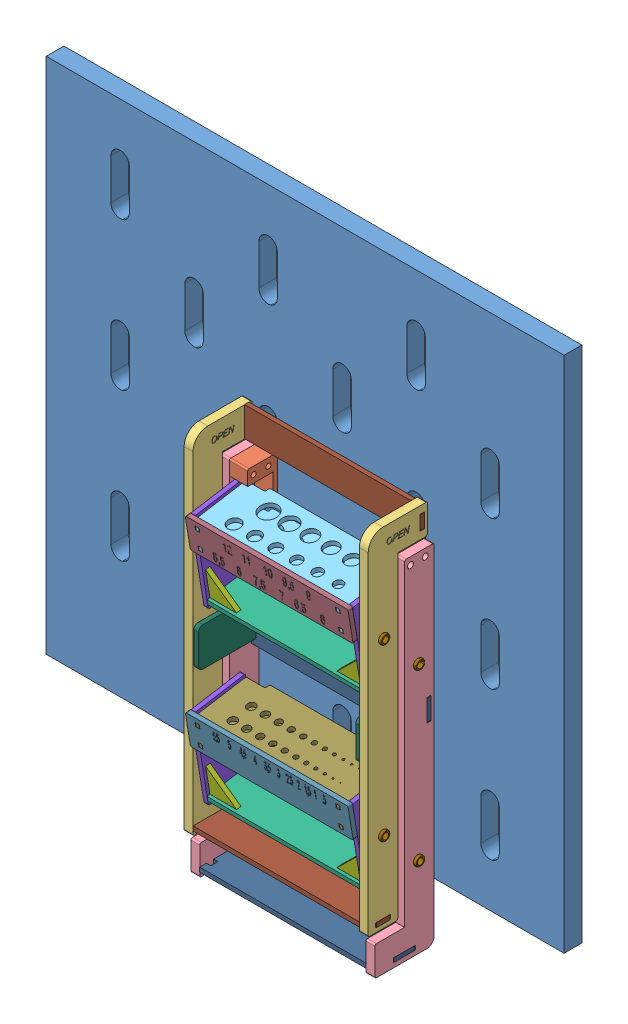
SolidWorks assembly 0 Органайзер свёрла, configuration По умолчанию. Lengths in mm.
Overall size (350 388.75 67.87).
37 component instances, 15 part files, 100 mates.
Components (placement in the parent):
- 1 Стенка-1: 1 Стенка [По умолчанию] at origin size (350 350 12)
- 2 Кронштейн свёрла-1: 2 Кронштейн свёрла [По умолчанию] at (43.8 136.25 12) size (12.4 30 35.1)
- 2 Кронштейн свёрла-2: 2 Кронштейн свёрла [По умолчанию] at (143.8 136.25 12) size (12.4 30 35.1)
- 4 Стенка подвижная свёрла-1: 4 Стенка подвижная свёрла [По умолчанию] at (37.8 -62.2036 36.5858) size (6 235 40)
- 4 Стенка подвижная свёрла-2: 4 Стенка подвижная свёрла [По умолчанию] at (156.2 -62.2036 36.5858) size (6 235 40)
- 3 Стенка основа свёрла-1: 3 Стенка основа свёрла [По умолчанию] at (37.8 146.25 12) size (6 235 40)
- 3 Стенка основа свёрла-2: 3 Стенка основа свёрла [По умолчанию] at (156.2 146.25 12) size (6 235 40)
- 7 Полка ячейки верхняя-2: 7 Полка ячейки верхняя [По умолчанию] at (100.2 129.8865 41.0226) x (-1 0 0) z (0 -0.986932 -0.161135) size (110 41 3)
- 6 Полка ячейки нижняя-2: 6 Полка ячейки нижняя [По умолчанию] at (100.2 72.7151 51.0412) x (1 0 0) z (0 -0.161135 0.986932) size (110 3 35)
- 10 Уголок свёрла-1: 10 Уголок свёрла [По умолчанию] at (45.2 86.3468 48.2259) x (1 0 0) z (0 -0.161135 0.986932) size (21 21 3)
- 10 Уголок свёрла-2: 10 Уголок свёрла [По умолчанию] at (142.2 73.5167 46.1312) x (0 0.986932 0.161135) z (0 -0.161135 0.986932) size (21 21 3)
- 5 Стенка ячейки-3: 5 Стенка ячейки [По умолчанию] at (152.2 102.3381 36.5754) x (0 0.161135 -0.986932) z (1 0 0) size (38 60 3)
- 5 Стенка ячейки-4: 5 Стенка ячейки [По умолчанию] at (45.2 102.3381 36.5754) x (0 0.161135 -0.986932) z (1 0 0) size (38 60 3)
- 9 штифт-1: 9 штифт [По умолчанию] at (44.3 107.7964 46.5858) x (-1 0 0) z (0 0.755067 -0.655647) size (14.3 7.8 7.8)
- 9 штифт-2: 9 штифт [По умолчанию] at (155.7 81.25 23) size (14.3 7.8 7.8)
- 9 штифт-4: 9 штифт [По умолчанию] at (44.3 81.25 23) x (-1 0 0) z (0 -0.824555 -0.565781) size (14.3 7.8 7.8)
- 9 штифт-5: 9 штифт [По умолчанию] at (155.7 107.7964 46.5858) x (1 0 0) z (0 -0.809118 0.587647) size (14.3 7.8 7.8)
- 6 Полка ячейки нижняя-5: 6 Полка ячейки нижняя [По умолчанию] at (100.275 -42.2849 51.0412) x (1 0 0) z (0 -0.161135 0.986932) size (110 3 35)
- 10 Уголок свёрла-7: 10 Уголок свёрла [По умолчанию] at (45.275 -28.6532 48.2259) x (1 0 0) z (0 -0.161135 0.986932) size (21 21 3)
- 5 Стенка ячейки-9: 5 Стенка ячейки [По умолчанию] at (152.2 -12.6619 36.5754) x (0 0.161135 -0.986932) z (1 0 0) size (38 60 3)
- 10 Уголок свёрла-8: 10 Уголок свёрла [По умолчанию] at (142.2 -41.4914 46.1805) x (0 0.986932 0.161135) z (0 -0.161135 0.986932) size (21 21 3)
- 5 Стенка ячейки-10: 5 Стенка ячейки [По умолчанию] at (45.275 -12.6619 36.5754) x (0 0.161135 -0.986932) z (1 0 0) size (38 60 3)
- 9 штифт-9: 9 штифт [По умолчанию] at (44.3 -7.2036 46.5858) x (-1 0 0) z (0 0.849471 -0.527636) size (14.3 7.8 7.8)
- 9 штифт-10: 9 штифт [По умолчанию] at (155.7 -33.75 23) x (1 0 0) z (0 0.562749 -0.826628) size (14.3 7.8 7.8)
- 9 штифт-11: 9 штифт [По умолчанию] at (44.3 -33.75 23) x (-1 0 0) z (0 -0.724419 -0.68936) size (14.3 7.8 7.8)
- 9 штифт-12: 9 штифт [По умолчанию] at (155.7 -7.2036 46.5858) x (1 0 0) z (0 -0.892056 0.451925) size (14.3 7.8 7.8)
- 11 низ-1: 11 низ [По умолчанию] at (99.95 -85.655 32.05) size (124.5 3 40)
- 12 верх-1: 12 верх [По умолчанию] at (99.95 162.8464 18.6808) x (1 0 0) z (0 -1 0) size (124.5 3 20)
- 7 Полка ячейки верхняя-6: 7 Полка ячейки верхняя [По умолчанию] at (100.2 117.0564 38.9278) x (-1 0 0) z (0 -0.986932 -0.161135) size (110 41 3)
- 7.1 Полка ячейки верхняя -1: 7.1 Полка ячейки верхняя  [По умолчанию] at (100.275 14.8865 41.0226) x (-1 0 0) z (0 -0.986932 -0.161135) size (110 41 3)
- 13.1 маркировка свёрла верх-1: 13.1 маркировка свёрла верх [По умолчанию] at (100.125 118.8555 58.4731) x (1 0 0) z (0 -0.161135 0.986932) size (110 22 3)
- 7.1 Полка ячейки верхняя -4: 7.1 Полка ячейки верхняя  [По умолчанию] at (100.275 2.0564 38.9278) x (-1 0 0) z (0 -0.986932 -0.161135) size (110 41 3)
- 13.2 маркировка свёрла низ-1: 13.2 маркировка свёрла низ [По умолчанию] at (100.2 3.8555 58.4731) x (1 0 0) z (0 -0.161135 0.986932) size (110 40.65 3)
- 12 верх-3: 12 верх [По умолчанию] at (100.05 -59.2986 46.5358) size (124.5 3 20)
- 11 низ-2: 11 низ [По умолчанию] at (99.95 50.7 13.915) x (1 0 0) z (0 -1 0) size (124.5 3 40)
- 14 направляюшая-1: 14 направляюшая [По умолчанию] at (156.2 50.625 36.415) x (0 0 1) z (-1 0 0) size (43.8 31 3)
- 14 направляюшая-2: 14 направляюшая [По умолчанию] at (46.8 50.625 36.415) x (0 0 1) z (-1 0 0) size (43.8 31 3)
Mates (geometry in assembly coordinates):
- Концентричный1: concentric anti-aligned: cylinder of 2 Кронштейн свёрла-2 through (156.2 141.25 28) axis (1 0 0) radius 1.7; cylinder of Стенка основа свёрла-2 through (162.2 141.25 28) axis (-1 0 0) radius 2
- Концентричный2: concentric anti-aligned: cylinder of 2 Кронштейн свёрла-2 through (156.2 141.25 18) axis (1 0 0) radius 1.7; cylinder of Стенка основа свёрла-2 through (162.2 141.25 18) axis (-1 0 0) radius 2
- Совпадение1: coincident anti-aligned: plane of 2 Кронштейн свёрла-2 through (156.2 136.25 12) normal (1 0 0); plane of Стенка основа свёрла-2 through (156.2 146.25 12) normal (-1 0 0)
- Концентричный3: concentric anti-aligned: cylinder of 2 Кронштейн свёрла-1 through (56.2 141.25 18) axis (1 0 0) radius 1.7; cylinder of 3 Стенка основа свёрла-1 through (43.8 141.25 18) axis (-1 0 0) radius 2
- Концентричный4: concentric anti-aligned: cylinder of 2 Кронштейн свёрла-1 through (56.2 141.25 28) axis (1 0 0) radius 1.7; cylinder of 3 Стенка основа свёрла-1 through (43.8 141.25 28) axis (-1 0 0) radius 2
- Совпадение2: coincident anti-aligned: plane of 2 Кронштейн свёрла-1 through (43.8 136.25 12) normal (-1 0 0); plane of 3 Стенка основа свёрла-1 through (43.8 146.25 12) normal (1 0 0)
- Концентричный7: concentric anti-aligned: cylinder of 1 Стенка-1 through (150 136.25 12) axis (0 0 -1) radius 6.25; cylinder of 2 Кронштейн свёрла-2 through (150 136.25 -23.513) axis (0 0 1) radius 6.2
- Концентричный9: concentric anti-aligned: cylinder of 1 Стенка-1 through (50 136.25 12) axis (0 0 -1) radius 6.25; cylinder of 2 Кронштейн свёрла-1 through (50 136.25 -23.513) axis (0 0 1) radius 6.2
- Совпадение15: coincident anti-aligned: plane of 1 Стенка-1 through (0 0 12) normal (0 0 1); plane of 2 Кронштейн свёрла-2 through (156.2 136.25 12) normal (0 0 -1)
- Параллельность1: parallel aligned: plane of 4 Стенка подвижная свёрла-1 through (43.8 172.7964 36.5858) normal (0 1 0); plane of 4 Стенка подвижная свёрла-2 through (162.2 172.7964 36.5858) normal (0 1 0)
- Совпадение18: coincident aligned: plane of 4 Стенка подвижная свёрла-1 through (43.8 -62.2036 36.5858) normal (1 0 0); plane of 3 Стенка основа свёрла-1 through (43.8 146.25 12) normal (1 0 0)
- Параллельность2: parallel aligned: plane of 4 Стенка подвижная свёрла-1 through (43.8 172.7964 36.5858) normal (0 1 0); plane of 4 Стенка подвижная свёрла-2 through (162.2 172.7964 36.5858) normal (0 1 0)
- Параллельность3: parallel aligned: plane of 1 Стенка-1 through (0 300 12) normal (0 1 0); plane of 4 Стенка подвижная свёрла-1 through (43.8 172.7964 36.5858) normal (0 1 0)
- Совпадение31: coincident anti-aligned: plane of 6 Полка ячейки нижняя-2 through (100.2 72.7151 51.0412) normal (0 -0.986932 -0.161135); plane of 5 Стенка ячейки-4 through (48.2 75.7847 32.2401) normal (0 0.986932 0.161135)
- Совпадение32: coincident anti-aligned: plane of 6 Полка ячейки нижняя-2 through (100.2 79.2208 29.812) normal (0 0.161135 -0.986932); plane of 5 Стенка ячейки-4 through (48.2 102.8134 33.664) normal (0 -0.161135 0.986932)
- Совпадение33: coincident aligned: plane of 6 Полка ячейки нижняя-2 through (45.2 75.6759 51.5246) normal (-1 0 0); plane of 5 Стенка ячейки-4 through (45.2 102.3381 36.5754) normal (-1 0 0)
- Совпадение34: coincident anti-aligned: plane of 6 Полка ячейки нижняя-2 through (100.2 75.6759 51.5246) normal (0 0.986932 0.161135); plane of 10 Уголок свёрла-1 through (45.2 75.9941 49.5754) normal (0 -0.986932 -0.161135)
- Совпадение35: coincident anti-aligned: plane of 10 Уголок свёрла-1 through (48.2 85.8634 51.1867) normal (-1 0 0); plane of 5 Стенка ячейки-4 through (48.2 102.3381 36.5754) normal (1 0 0)
- Совпадение36: coincident anti-aligned: plane of 10 Уголок свёрла-1 through (45.2 86.3468 48.2259) normal (0 0.161135 -0.986932); plane of 5 Стенка ячейки-4 through (48.2 100.0701 50.4665) normal (0 -0.161135 0.986932)
- Совпадение38: coincident anti-aligned: plane of 10 Уголок свёрла-2 through (152.2 73.0333 49.092) normal (1 0 0); plane of 5 Стенка ячейки-3 through (152.2 102.3381 36.5754) normal (-1 0 0)
- Совпадение39: coincident anti-aligned: plane of 6 Полка ячейки нижняя-2 through (100.2 75.6759 51.5246) normal (0 0.986932 0.161135); plane of 10 Уголок свёрла-2 through (142.2 75.9941 49.5754) normal (0 -0.986932 -0.161135)
- Совпадение40: coincident anti-aligned: plane of 10 Уголок свёрла-2 through (142.2 73.5167 46.1312) normal (0 0.161135 -0.986932); plane of 5 Стенка ячейки-3 through (155.2 100.0701 50.4665) normal (0 -0.161135 0.986932)
- Концентричный12: concentric aligned: cylinder of 3 Стенка основа свёрла-1 through (43.8 81.25 23) axis (-1 0 0) radius 3; cylinder of 5 Стенка ячейки-4 through (48.2 81.25 23) axis (-1 0 0) radius 3
- Концентричный13: concentric aligned: cylinder of 4 Стенка подвижная свёрла-1 through (43.8 107.7964 46.5858) axis (-1 0 0) radius 3; cylinder of 5 Стенка ячейки-4 through (48.2 107.7964 46.5858) axis (-1 0 0) radius 3
- Концентричный14: concentric aligned: cylinder of 4 Стенка подвижная свёрла-2 through (162.2 107.7964 46.5858) axis (-1 0 0) radius 3; cylinder of 5 Стенка ячейки-3 through (155.2 107.7964 46.5858) axis (-1 0 0) radius 3
- Совпадение42: coincident aligned: plane of 4 Стенка подвижная свёрла-2 through (156.2 -62.2036 36.5858) normal (-1 0 0); plane of Стенка основа свёрла-2 through (156.2 146.25 12) normal (-1 0 0)
- Совпадение43: coincident anti-aligned: plane of 1 Стенка-1 through (0 0 12) normal (0 0 1); plane of 3 Стенка основа свёрла-1 through (43.8 146.25 12) normal (0 0 -1)
- Концентричный20: concentric aligned: cylinder of 5 Стенка ячейки-3 through (155.2 81.25 23) axis (-1 0 0) radius 3; cylinder of 9 штифт-2 through (153.8908 81.25 23) axis (-1 0 0) radius 2.9
- Совпадение81: coincident anti-aligned: plane of Стенка основа свёрла-2 through (156.2 146.25 12) normal (-1 0 0); plane of 9 штифт-2 through (156.2 78.35 23) normal (1 0 0)
- Концентричный21: concentric anti-aligned: cylinder of 3 Стенка основа свёрла-1 through (43.8 81.25 23) axis (-1 0 0) radius 3; cylinder of 9 штифт-4 through (46.1092 81.25 23) axis (1 0 0) radius 2.9
- Совпадение82: coincident anti-aligned: plane of 3 Стенка основа свёрла-1 through (43.8 146.25 12) normal (1 0 0); plane of 9 штифт-4 through (43.8 79.6092 25.3912) normal (-1 0 0)
- Совпадение83: coincident anti-aligned: plane of 5 Стенка ячейки-3 through (155.2 102.3381 36.5754) normal (1 0 0); plane of 9 штифт-2 through (155.2 78.35 23) normal (-1 0 0)
- Концентричный22: concentric aligned: cylinder of 4 Стенка подвижная свёрла-2 through (162.2 107.7964 46.5858) axis (-1 0 0) radius 3; cylinder of 9 штифт-5 through (153.8908 107.7964 46.5858) axis (-1 0 0) radius 2.9
- Совпадение84: coincident anti-aligned: plane of 4 Стенка подвижная свёрла-2 through (156.2 -62.2036 36.5858) normal (-1 0 0); plane of 9 штифт-5 through (156.2 106.0922 44.2393) normal (1 0 0)
- Концентричный23: concentric anti-aligned: cylinder of 4 Стенка подвижная свёрла-1 through (43.8 107.7964 46.5858) axis (-1 0 0) radius 3; cylinder of 9 штифт-1 through (46.1092 107.7964 46.5858) axis (1 0 0) radius 2.9
- Совпадение85: coincident anti-aligned: plane of 4 Стенка подвижная свёрла-1 through (43.8 -62.2036 36.5858) normal (1 0 0); plane of 9 штифт-1 through (43.8 105.895 44.3961) normal (-1 0 0)
- Совпадение95: coincident anti-aligned: plane of 6 Полка ячейки нижняя-5 through (100.275 -42.2849 51.0412) normal (0 -0.986932 -0.161135); plane of 5 Стенка ячейки-10 through (48.275 -39.2153 32.2401) normal (0 0.986932 0.161135)
- Совпадение96: coincident anti-aligned: plane of 6 Полка ячейки нижняя-5 through (100.275 -35.7792 29.812) normal (0 0.161135 -0.986932); plane of 5 Стенка ячейки-10 through (48.275 -12.1866 33.664) normal (0 -0.161135 0.986932)
- Совпадение97: coincident aligned: plane of 6 Полка ячейки нижняя-5 through (45.275 -39.3241 51.5246) normal (-1 0 0); plane of 5 Стенка ячейки-10 through (45.275 -12.6619 36.5754) normal (-1 0 0)
- Совпадение98: coincident anti-aligned: plane of 6 Полка ячейки нижняя-5 through (100.275 -39.3241 51.5246) normal (0 0.986932 0.161135); plane of 10 Уголок свёрла-7 through (45.275 -39.0059 49.5754) normal (0 -0.986932 -0.161135)
- Совпадение99: coincident anti-aligned: plane of 10 Уголок свёрла-7 through (48.275 -29.1366 51.1867) normal (-1 0 0); plane of 5 Стенка ячейки-10 through (48.275 -12.6619 36.5754) normal (1 0 0)
- Совпадение100: coincident anti-aligned: plane of 10 Уголок свёрла-7 through (45.275 -28.6532 48.2259) normal (0 0.161135 -0.986932); plane of 5 Стенка ячейки-10 through (48.275 -14.9299 50.4665) normal (0 -0.161135 0.986932)
- Совпадение101: coincident anti-aligned: plane of 5 Стенка ячейки-9 through (152.2 -12.6619 36.5754) normal (-1 0 0); plane of 10 Уголок свёрла-8 through (152.2 -41.9748 49.1413) normal (1 0 0)
- Совпадение102: coincident anti-aligned: plane of 6 Полка ячейки нижняя-5 through (100.275 -39.3241 51.5246) normal (0 0.986932 0.161135); plane of 10 Уголок свёрла-8 through (142.2 -39.014 49.6247) normal (0 -0.986932 -0.161135)
- Концентричный25: concentric aligned: cylinder of 3 Стенка основа свёрла-1 through (43.8 -33.75 23) axis (-1 0 0) radius 3; cylinder of 5 Стенка ячейки-10 through (48.275 -33.75 23) axis (-1 0 0) radius 3
- Концентричный26: concentric aligned: cylinder of 4 Стенка подвижная свёрла-1 through (43.8 -7.2036 46.5858) axis (-1 0 0) radius 3; cylinder of 5 Стенка ячейки-10 through (48.275 -7.2036 46.5858) axis (-1 0 0) radius 3
- Совпадение105: coincident anti-aligned: plane of Стенка основа свёрла-2 through (156.2 146.25 12) normal (-1 0 0); plane of 9 штифт-10 through (156.2 -31.3528 24.632) normal (1 0 0)
- Концентричный28: concentric anti-aligned: cylinder of 3 Стенка основа свёрла-1 through (43.8 -33.75 23) axis (-1 0 0) radius 3; cylinder of 9 штифт-11 through (46.1092 -33.75 23) axis (1 0 0) radius 2.9
- Совпадение106: coincident anti-aligned: plane of 3 Стенка основа свёрла-1 through (43.8 146.25 12) normal (1 0 0); plane of 9 штифт-11 through (43.8 -35.7491 25.1008) normal (-1 0 0)
- Концентричный29: concentric aligned: cylinder of 4 Стенка подвижная свёрла-2 through (162.2 -7.2036 46.5858) axis (-1 0 0) radius 3; cylinder of 9 штифт-12 through (153.8908 -7.2036 46.5858) axis (-1 0 0) radius 2.9
- Совпадение107: coincident anti-aligned: plane of 4 Стенка подвижная свёрла-2 through (156.2 -62.2036 36.5858) normal (-1 0 0); plane of 9 штифт-12 through (156.2 -8.5142 43.9988) normal (1 0 0)
- Концентричный30: concentric anti-aligned: cylinder of 4 Стенка подвижная свёрла-1 through (43.8 -7.2036 46.5858) axis (-1 0 0) radius 3; cylinder of 9 штифт-9 through (46.1092 -7.2036 46.5858) axis (1 0 0) radius 2.9
- Совпадение108: coincident anti-aligned: plane of 4 Стенка подвижная свёрла-1 through (43.8 -62.2036 36.5858) normal (1 0 0); plane of 9 штифт-9 through (43.8 -8.7337 44.1223) normal (-1 0 0)
- Совпадение128: coincident aligned: plane of Стенка основа свёрла-2 through (162.2 146.25 12) normal (1 0 0); plane of 11 низ-1 through (162.2 -82.655 32.05) normal (1 0 0)
- Совпадение129: coincident anti-aligned: plane of Стенка основа свёрла-2 through (162.2 146.25 24.55) normal (0 0 1); plane of 11 низ-1 through (99.95 -82.655 24.55) normal (0 0 -1)
- Совпадение130: coincident anti-aligned: plane of Стенка основа свёрла-2 through (162.2 -85.655 12) normal (0 1 0); plane of 11 низ-1 through (99.95 -85.655 32.05) normal (0 -1 0)
- Совпадение131: coincident anti-aligned: plane of 4 Стенка подвижная свёрла-2 through (162.2 -62.2036 18.6808) normal (0 0 1); plane of 12 верх-1 through (99.95 162.8464 18.6808) normal (0 0 -1)
- Совпадение132: coincident anti-aligned: plane of 4 Стенка подвижная свёрла-2 through (162.2 157.8464 36.5858) normal (0 1 0); plane of 12 верх-1 through (99.95 157.8464 21.6808) normal (0 -1 0)
- Совпадение133: coincident aligned: plane of 4 Стенка подвижная свёрла-2 through (162.2 -62.2036 36.5858) normal (1 0 0); plane of 12 верх-1 through (162.2 162.8464 21.6808) normal (1 0 0)
- Совпадение134: coincident anti-aligned: plane of 5 Стенка ячейки-4 through (48.2 117.0483 38.9771) normal (0 -0.986932 -0.161135); plane of 7 Полка ячейки верхняя-6 through (100.2 117.0564 38.9278) normal (0 0.986932 0.161135)
- Совпадение135: coincident anti-aligned: plane of 5 Стенка ячейки-4 through (48.2 101.5405 41.4607) normal (0 0.161135 -0.986932); plane of 7 Полка ячейки верхняя-6 through (100.2 113.2899 43.3791) normal (0 -0.161135 0.986932)
- Совпадение136: coincident aligned: plane of 5 Стенка ячейки-4 through (45.2 102.3381 36.5754) normal (-1 0 0); plane of 7 Полка ячейки верхняя-6 through (45.2 114.0956 38.4444) normal (-1 0 0)
- Совпадение137: coincident anti-aligned: plane of 7 Полка ячейки верхняя-2 through (100.2 129.8865 41.0226) normal (0 0.986932 0.161135); plane of 5 Стенка ячейки-4 through (48.2 129.8784 41.0719) normal (0 -0.986932 -0.161135)
- Совпадение138: coincident anti-aligned: plane of 7 Полка ячейки верхняя-2 through (100.2 126.12 45.4738) normal (0 -0.161135 0.986932); plane of 5 Стенка ячейки-4 through (48.2 101.5405 41.4607) normal (0 0.161135 -0.986932)
- Совпадение139: coincident anti-aligned: plane of 7 Полка ячейки верхняя-2 through (48.2 126.9257 40.5392) normal (-1 0 0); plane of 5 Стенка ячейки-4 through (48.2 102.3381 36.5754) normal (1 0 0)
- Совпадение140: coincident anti-aligned: plane of 7 Полка ячейки верхняя-2 through (100.2 126.12 45.4738) normal (0 -0.161135 0.986932); plane of 5 Стенка ячейки-3 through (155.2 101.5405 41.4607) normal (0 0.161135 -0.986932)
- Совпадение141: coincident anti-aligned: plane of 7 Полка ячейки верхняя-2 through (100.2 129.8865 41.0226) normal (0 0.986932 0.161135); plane of 5 Стенка ячейки-3 through (155.2 129.8784 41.0719) normal (0 -0.986932 -0.161135)
- Совпадение142: coincident anti-aligned: plane of 7 Полка ячейки верхняя-2 through (152.2 126.9257 40.5392) normal (1 0 0); plane of 5 Стенка ячейки-3 through (152.2 102.3381 36.5754) normal (-1 0 0)
- Совпадение154: coincident anti-aligned: plane of 5 Стенка ячейки-10 through (48.275 14.8784 41.0719) normal (0 -0.986932 -0.161135); plane of 7.1 Полка ячейки верхняя -1 through (100.275 14.8865 41.0226) normal (0 0.986932 0.161135)
- Совпадение155: coincident anti-aligned: plane of 5 Стенка ячейки-10 through (48.275 -12.6619 36.5754) normal (1 0 0); plane of 7.1 Полка ячейки верхняя -1 through (48.275 11.9257 40.5392) normal (-1 0 0)
- Совпадение156: coincident anti-aligned: plane of 5 Стенка ячейки-10 through (48.275 -13.4595 41.4607) normal (0 0.161135 -0.986932); plane of 7.1 Полка ячейки верхняя -1 through (100.275 11.12 45.4738) normal (0 -0.161135 0.986932)
- Совпадение160: coincident anti-aligned: plane of 7 Полка ячейки верхняя-2 through (100.2 123.8641 59.2909) normal (0 -0.161135 0.986932); plane of 13.1 маркировка свёрла верх-1 through (100.125 118.8555 58.4731) normal (0 0.161135 -0.986932)
- Совпадение169: coincident anti-aligned: plane of 6 Полка ячейки нижняя-5 through (142.2 -39.3241 51.5246) normal (-1 0 0); plane of 10 Уголок свёрла-8 through (142.2 -41.9748 49.1413) normal (1 0 0)
- Совпадение170: coincident anti-aligned: plane of 6 Полка ячейки нижняя-5 through (100.275 -38.5306 46.6639) normal (0 -0.161135 0.986932); plane of 10 Уголок свёрла-8 through (142.2 -41.4914 46.1805) normal (0 0.161135 -0.986932)
- Совпадение171: coincident anti-aligned: plane of 5 Стенка ячейки-9 through (155.2 14.8784 41.0719) normal (0 -0.986932 -0.161135); plane of 7.1 Полка ячейки верхняя -1 through (100.275 14.8865 41.0226) normal (0 0.986932 0.161135)
- Совпадение172: coincident anti-aligned: plane of 5 Стенка ячейки-9 through (155.2 -13.4595 41.4607) normal (0 0.161135 -0.986932); plane of 7.1 Полка ячейки верхняя -1 through (100.275 11.12 45.4738) normal (0 -0.161135 0.986932)
- Совпадение173: coincident anti-aligned: plane of 5 Стенка ячейки-9 through (155.2 -12.6619 36.5754) normal (1 0 0); plane of 9 штифт-12 through (155.2 -8.5142 43.9988) normal (-1 0 0)
- Концентричный31: concentric aligned: cylinder of Стенка основа свёрла-2 through (162.2 -33.75 23) axis (-1 0 0) radius 3; cylinder of 9 штифт-10 through (153.8908 -33.75 23) axis (-1 0 0) radius 2.9
- Совпадение174: coincident anti-aligned: plane of 5 Стенка ячейки-10 through (48.275 2.0483 38.9771) normal (0 -0.986932 -0.161135); plane of 7.1 Полка ячейки верхняя -4 through (100.275 2.0564 38.9278) normal (0 0.986932 0.161135)
- Совпадение175: coincident anti-aligned: plane of 5 Стенка ячейки-10 through (48.275 -12.6619 36.5754) normal (1 0 0); plane of 7.1 Полка ячейки верхняя -4 through (48.275 -0.9044 38.4444) normal (-1 0 0)
- Совпадение176: coincident anti-aligned: plane of 5 Стенка ячейки-10 through (48.275 -13.4595 41.4607) normal (0 0.161135 -0.986932); plane of 7.1 Полка ячейки верхняя -4 through (100.275 -1.7101 43.3791) normal (0 -0.161135 0.986932)
- Совпадение177: coincident anti-aligned: plane of 5 Стенка ячейки-9 through (155.2 2.0483 38.9771) normal (0 -0.986932 -0.161135); plane of 7.1 Полка ячейки верхняя -4 through (100.275 2.0564 38.9278) normal (0 0.986932 0.161135)
- Совпадение178: coincident anti-aligned: plane of 5 Стенка ячейки-9 through (155.2 -13.4595 41.4607) normal (0 0.161135 -0.986932); plane of 7.1 Полка ячейки верхняя -4 through (100.275 -1.7101 43.3791) normal (0 -0.161135 0.986932)
- Совпадение182: coincident anti-aligned: plane of 7 Полка ячейки верхняя-2 through (146.2 126.9257 40.5392) normal (-1 0 0); plane of 13.1 маркировка свёрла верх-1 through (146.2 118.372 61.4339) normal (1 0 0)
- Совпадение183: coincident anti-aligned: plane of 7 Полка ячейки верхняя-2 through (100.2 126.9257 40.5392) normal (0 -0.986932 -0.161135); plane of 13.1 маркировка свёрла верх-1 through (100.125 123.3807 62.2517) normal (0 0.986932 0.161135)
- Совпадение184: coincident anti-aligned: plane of 7.1 Полка ячейки верхняя -1 through (51.275 11.9257 40.5392) normal (-1 0 0); plane of 13.2 маркировка свёрла низ-1 through (51.275 3.372 61.4339) normal (1 0 0)
- Совпадение185: coincident aligned: plane of 7.1 Полка ячейки верхняя -1 through (100.275 8.3807 62.2517) normal (0 -0.161135 0.986932); plane of 13.2 маркировка свёрла низ-1 through (100.2 3.372 61.4339) normal (0 -0.161135 0.986932)
- Совпадение186: coincident anti-aligned: plane of 7.1 Полка ячейки верхняя -1 through (100.275 11.9257 40.5392) normal (0 -0.986932 -0.161135); plane of 13.2 маркировка свёрла низ-1 through (100.2 8.3807 62.2517) normal (0 0.986932 0.161135)
- Совпадение191: coincident aligned: plane of 4 Стенка подвижная свёрла-1 through (37.8 -62.2036 36.5858) normal (-1 0 0); plane of 12 верх-3 through (37.8 -56.2986 46.5358) normal (-1 0 0)
- Совпадение192: coincident anti-aligned: plane of 4 Стенка подвижная свёрла-1 through (43.8 -56.2986 36.5858) normal (0 -1 0); plane of 12 верх-3 through (100.05 -56.2986 46.5358) normal (0 1 0)
- Совпадение193: coincident anti-aligned: plane of 4 Стенка подвижная свёрла-1 through (43.8 -62.2036 51.5358) normal (0 0 -1); plane of 12 верх-3 through (100.05 -56.2986 51.5358) normal (0 0 1)
- Совпадение194: coincident anti-aligned: plane of 3 Стенка основа свёрла-2 through (162.2 146.25 16.915) normal (0 0 -1); plane of 11 низ-2 through (99.95 50.7 16.915) normal (0 0 1)
- Совпадение195: coincident aligned: plane of 3 Стенка основа свёрла-2 through (162.2 146.25 12) normal (1 0 0); plane of 11 низ-2 through (162.2 50.7 16.915) normal (1 0 0)
- Совпадение196: coincident anti-aligned: plane of 3 Стенка основа свёрла-2 through (162.2 58.2 12) normal (0 -1 0); plane of 11 низ-2 through (99.95 58.2 16.915) normal (0 1 0)
- Совпадение197: coincident anti-aligned: plane of 3 Стенка основа свёрла-2 through (156.2 146.25 12) normal (-1 0 0); plane of 14 направляюшая-1 through (156.2 50.625 36.415) normal (1 0 0)
- Совпадение198: coincident anti-aligned: plane of 11 низ-2 through (99.95 66.125 16.915) normal (0 -1 0); plane of 14 направляюшая-1 through (153.2 66.125 36.415) normal (0 1 0)
- Совпадение199: coincident aligned: line of 11 низ-2; line of 14 направляюшая-1 through (153.2 61.125 16.915) axis (0 -1 0)
- Совпадение202: coincident anti-aligned: plane of 11 низ-2 through (99.95 66.125 16.915) normal (0 -1 0); plane of 14 направляюшая-2 through (43.8 66.125 36.415) normal (0 1 0)
- Совпадение204: coincident anti-aligned: plane of 3 Стенка основа свёрла-1 through (43.8 146.25 12) normal (1 0 0); plane of 14 направляюшая-2 through (43.8 50.625 36.415) normal (-1 0 0)
- Совпадение205: coincident: plane of 11 низ-2 through (99.95 50.7 16.915) normal (0 0 1); line of 14 направляюшая-2 through (46.8 61.125 16.915) axis (0 -1 0)
